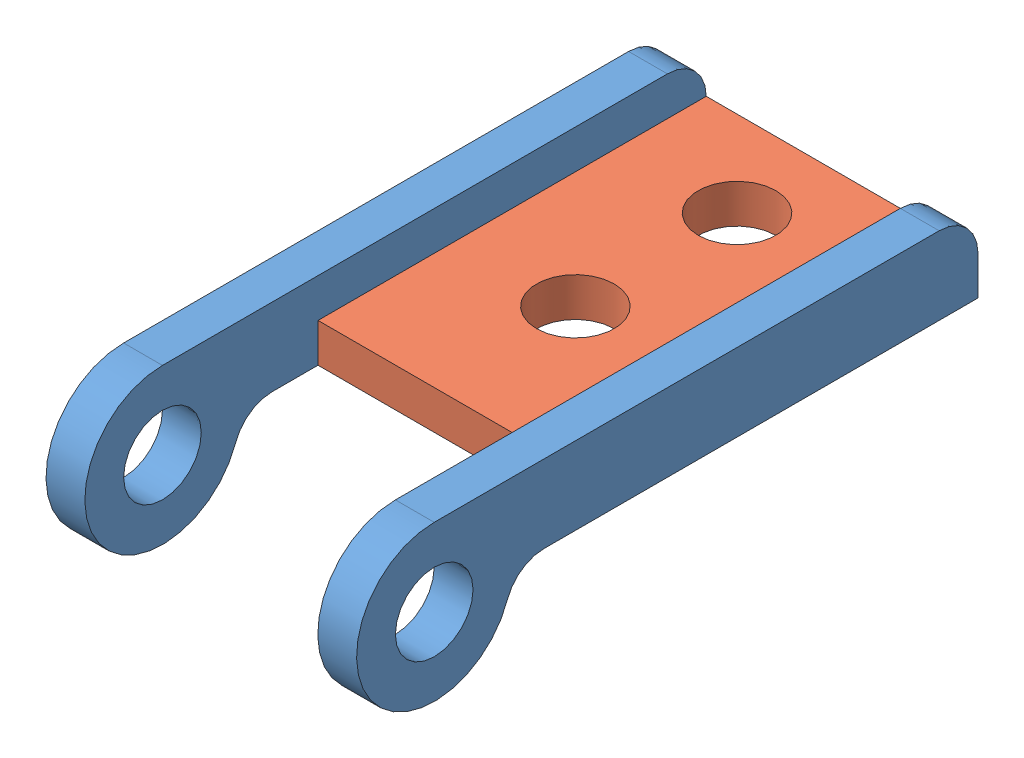
SolidWorks assembly Trunk hinge 3, configuration Default. Lengths in mm.
Overall size (25.4 12.7 50.82).
3 component instances, 2 part files, 3 mates.
Components (placement in the parent):
- Trunk Hinge side-1: Trunk Hinge side [Default] at (5.408 -10.0859 7.8224) x (0 0 1) z (-1 0 0) size (50.82 12.7 3.17)
- Trunk Hinge side-2: Trunk Hinge side [Default] at (-16.817 -10.0859 7.8224) x (0 0 1) z (-1 0 0) size (50.82 12.7 3.17)
- Trunk Hinge base-2: Trunk Hinge base [Default] at (35.7927 -10.0859 29.8462) size (19.05 3.17 31.75)
Mates (geometry in assembly coordinates):
- Coincident7: coincident anti-aligned: plane of Trunk Hinge side-1 through (2.233 -10.0859 7.8224) normal (-1 0 0); plane of Trunk Hinge base-2 through (2.233 -6.9109 29.8462) normal (1 0 0)
- Coincident8: coincident aligned: plane of Trunk Hinge side-1 through (2.233 -10.0859 7.8224) normal (0 -1 0); plane of Trunk Hinge base-2 through (35.7927 -10.0859 29.8462) normal (0 -1 0)
- Coincident9: coincident aligned: plane of Trunk Hinge side-1 through (2.233 -10.0859 -36.6484) normal (0 0 -1); plane of Trunk Hinge base-2 through (35.7927 -6.9109 -36.6484) normal (0 0 -1)
